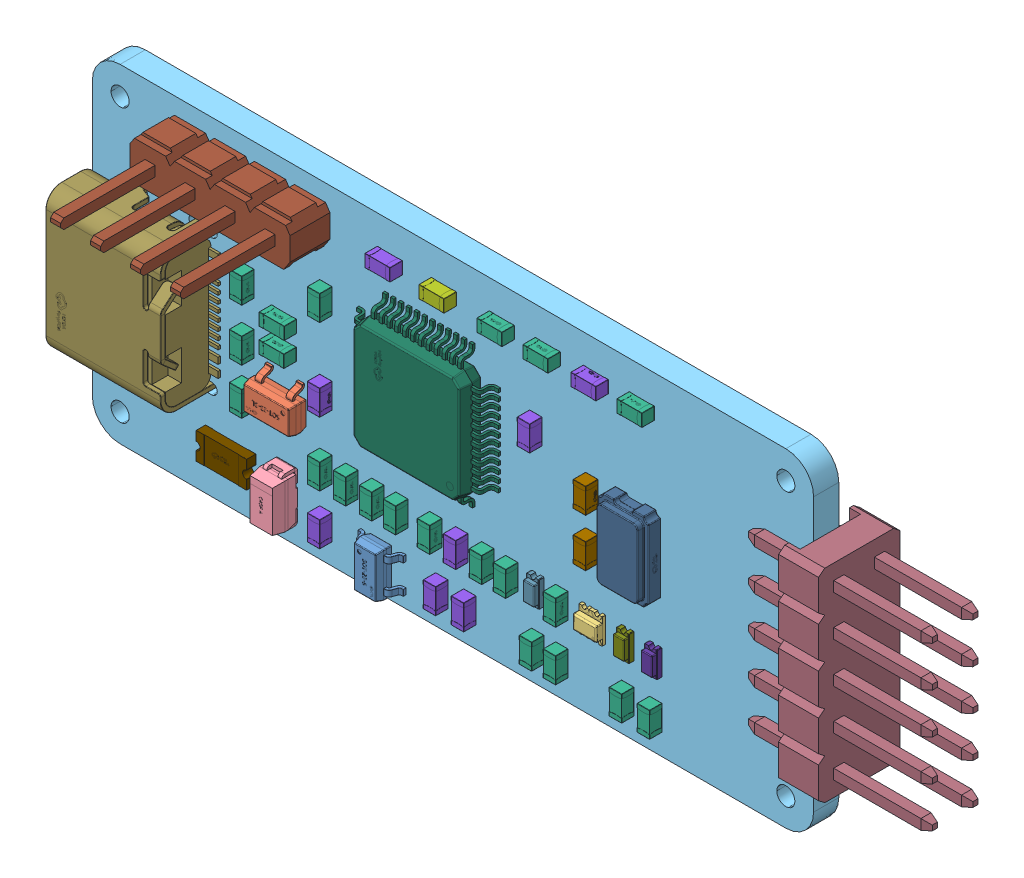
SolidWorks assembly 3D_ST-LINK  V2-1_1_2025-01-13, configuration 默认. Lengths in mm.
Overall size (53.96 20.88 11.97).
51 component instances, 18 part files, 0 mates.
Components (placement in the parent):
- 3D_ST-LINK  V2-1_1_2025-01-13.step-1: 3D_ST-LINK  V2-1_1_2025-01-13.step [默认] at origin size (53.96 20.88 11.97)
  - S64j-U1-SOT-23-5_L3.0-W1.7-P0.95-LS2.8-BR.step-1: S64j-U1-SOT-23-5_L3.0-W1.7-P0.95-LS2.8-BR.step [默认] at (18.5179 2.032 1.6) x (-1 0 0) z (0 0 1) size (2.89 2.78 1.2)
    - COMPOUND.step-1: COMPOUND.step [默认] at origin size (2.89 2.78 1.2)
  - S64j-Q1-SOT-23(SOT-23-3).step-1: S64j-Q1-SOT-23(SOT-23-3).step [默认] at (12.319 6.604 1.6) x (-1 0 0) z (0 0 1) size (3.01 2.92 1.27)
    - COMPOUND-0.step-1: COMPOUND-0.step [默认] at origin size (3.01 2.92 1.27)
  - S64j-LED1-LED-ARRAY-SMD_4P-L1.6-W1.5-TR-RD_TJ-S1615SW6TGLCRB-A5.step-1: S64j-LED1-LED-ARRAY-SMD_4P-L1.6-W1.5-TR-RD_TJ-S1615SW6TGLCRB-A5.step [默认] at (31.8771 5.334 1.6) x (0 -1 0) z (0 0 1) size (1.62 1.51 0.61)
    - COMPOUND-1.step-1: COMPOUND-1.step [默认] at origin size (1.62 1.51 0.61)
  - S64j-C1-CASE-A_3216.step-1: S64j-C1-CASE-A_3216.step [默认] at (12.446 2.921 1.6) x (0 -1 0) z (0 0 1) size (3.2 1.6 1.7)
    - COMPOUND-2.step-1: COMPOUND-2.step [默认] at origin size (3.2 1.6 1.7)
  - S64j-Board.step-1: S64j-Board.step [默认] at origin size (45.82 20.88 1.6)
  - S64j-R12-R0603.step-1: S64j-R12-R0603.step [默认] at (35.8141 2.286 1.6) x (0 1 0) z (0 0 1) size (1.6 0.8 0.8)
  - S64j-R12-R0603.step-2: S64j-R12-R0603.step [默认] at (34.0361 2.286 1.6) x (0 1 0) z (0 0 1) size (1.6 0.8 0.8)
  - S64j-R12-R0603.step-3: S64j-R12-R0603.step [默认] at (29.8451 2.2946 1.6) x (0 1 0) z (0 0 1) size (1.6 0.8 0.8)
  - S64j-R12-R0603.step-4: S64j-R12-R0603.step [默认] at (14.859 14.732 1.6) x (0 1 0) z (0 0 1) size (1.6 0.8 0.8)
  - S64j-R12-R0603.step-5: S64j-R12-R0603.step [默认] at (28.9561 18.796 1.6) size (1.6 0.8 0.8)
  - S64j-R12-R0603.step-6: S64j-R12-R0603.step [默认] at (26.0351 18.796 1.6) size (1.6 0.8 0.8)
  - S64j-R12-R0603.step-7: S64j-R12-R0603.step [默认] at (29.8451 5.461 1.6) x (0 -1 0) z (0 0 1) size (1.6 0.8 0.8)
  - S64j-R12-R0603.step-8: S64j-R12-R0603.step [默认] at (25.1461 5.461 1.6) x (0 1 0) z (0 0 1) size (1.6 0.8 0.8)
  - S64j-R12-R0603.step-9: S64j-R12-R0603.step [默认] at (18.161 5.461 1.6) x (0 -1 0) z (0 0 1) size (1.6 0.8 0.8)
  - S64j-R12-R0603.step-10: S64j-R12-R0603.step [默认] at (14.859 5.461 1.6) x (0 -1 0) z (0 0 1) size (1.6 0.8 0.8)
  - S64j-R12-R0603.step-11: S64j-R12-R0603.step [默认] at (21.844 5.4696 1.6) x (0 -1 0) z (0 0 1) size (1.6 0.8 0.8)
  - S64j-R12-R0603.step-12: S64j-R12-R0603.step [默认] at (16.51 5.461 1.6) x (0 -1 0) z (0 0 1) size (1.6 0.8 0.8)
  - S64j-R12-R0603.step-13: S64j-R12-R0603.step [默认] at (19.685 5.461 1.6) x (0 1 0) z (0 0 1) size (1.6 0.8 0.8)
  - S64j-R12-R0603.step-14: S64j-R12-R0603.step [默认] at (9.906 13.208 1.6) x (0 -1 0) z (0 0 1) size (1.6 0.8 0.8)
  - S64j-R12-R0603.step-15: S64j-R12-R0603.step [默认] at (9.906 6.985 1.6) x (0 1 0) z (0 0 1) size (1.6 0.8 0.8)
  - S64j-R12-R0603.step-16: S64j-R12-R0603.step [默认] at (26.6701 5.461 1.6) x (0 1 0) z (0 0 1) size (1.6 0.8 0.8)
  - S64j-R12-R0603.step-17: S64j-R12-R0603.step [默认] at (9.906 9.906 1.6) x (0 -1 0) z (0 0 1) size (1.6 0.8 0.8)
  - S64j-R12-R0603.step-18: S64j-R12-R0603.step [默认] at (34.9251 18.796 1.6) size (1.6 0.8 0.8)
  - S64j-R12-R0603.step-19: S64j-R12-R0603.step [默认] at (12.2027 12.2134 1.6) size (1.6 0.8 0.8)
  - S64j-R12-R0603.step-20: S64j-R12-R0603.step [默认] at (12.1844 10.668 1.6) size (1.6 0.8 0.8)
  - S64j-R22-R0603.step-1: S64j-R22-R0603.step [默认] at (22.352 18.796 1.6) x (-1 0 0) z (0 0 1) size (1.6 0.8 0.8)
  - S64j-R12-R0603.step-21: S64j-R12-R0603.step [默认] at (28.3211 2.286 1.6) x (0 1 0) z (0 0 1) size (1.6 0.8 0.8)
  - S64j-C2-C0603.step-1: S64j-C2-C0603.step [默认] at (14.859 2.286 1.6) x (0 1 0) z (0 0 1) size (1.6 0.8 0.8)
  - S64j-C2-C0603.step-2: S64j-C2-C0603.step [默认] at (22.225 2.286 1.6) x (0 1 0) z (0 0 1) size (1.6 0.8 0.8)
  - S64j-C5-C0603.step-1: S64j-C5-C0603.step [默认] at (31.7501 12.573 1.6) x (0 -1 0) z (0 0 1) size (1.6 0.8 0.8)
  - S64j-C2-C0603.step-3: S64j-C2-C0603.step [默认] at (32.0041 18.796 1.6) size (1.6 0.8 0.8)
  - S64j-C2-C0603.step-4: S64j-C2-C0603.step [默认] at (18.923 18.796 1.6) x (-1 0 0) z (0 0 1) size (1.6 0.8 0.8)
  - S64j-C2-C0603.step-5: S64j-C2-C0603.step [默认] at (14.859 9.525 1.6) x (0 -1 0) z (0 0 1) size (1.6 0.8 0.8)
  - S64j-C2-C0603.step-6: S64j-C2-C0603.step [默认] at (23.495 5.461 1.6) x (0 1 0) z (0 0 1) size (1.6 0.8 0.8)
  - S64j-C2-C0603.step-7: S64j-C2-C0603.step [默认] at (28.1941 14.224 1.6) x (0 1 0) z (0 0 1) size (1.6 0.8 0.8)
  - S64j-C2-C0603.step-8: S64j-C2-C0603.step [默认] at (24.003 2.286 1.6) x (0 1 0) z (0 0 1) size (1.6 0.8 0.8)
  - S64j-C5-C0603.step-2: S64j-C5-C0603.step [默认] at (31.7501 9.525 1.6) x (0 1 0) z (0 0 1) size (1.6 0.8 0.8)
  - S64j-X1-OSC-SMD_L5.0-W3.2.step-1: S64j-X1-OSC-SMD_L5.0-W3.2.step [默认] at (34.5548 11.0631 1.6) x (0 -1 0) z (0 0 1) size (5 3.2 1.21)
  - S64j-H2-HDR-TH_4P-P2.54-V-M.step-1: S64j-H2-HDR-TH_4P-P2.54-V-M.step [默认] at (10.033 18.796 1.6) x (-1 0 0) z (0 0 1) size (10.17 2.66 11.54)
  - S64j-USB1-USB-3.1-SMD_U262-161N-4BVC11.step-1: S64j-USB1-USB-3.1-SMD_U262-161N-4BVC11.step [默认] at (5.334 10.414 1.6) x (0 -1 0) z (0 0 1) size (8.94 7.9 4.1)
  - S64j-H3-HDR-TH_SMD-10P-P2.54.step-1: S64j-H3-HDR-TH_SMD-10P-P2.54.step [默认] at (42.7991 10.541 1.6) size (11.68 12.9 5.16)
  - S64j-LED2-LED0603.step-1: S64j-LED2-LED0603.step [默认] at (28.3211 5.461 1.6) x (0 -1 0) z (0 0 1) size (1.62 0.8 0.6)
  - S64j-U2-LQFP-48_L7.0-W7.0-P0.50-LS9.0-BL.step-1: S64j-U2-LQFP-48_L7.0-W7.0-P0.50-LS9.0-BL.step [默认] at (21.4566 12.446 1.6) x (0 1 0) z (0 0 1) size (9 9 1.5)
  - S64j-LED3-LED0603.step-1: S64j-LED3-LED0603.step [默认] at (34.0361 5.334 1.6) x (0 -1 0) z (0 0 1) size (1.62 0.8 0.6)
  - S64j-LED4-LED0603.step-1: S64j-LED4-LED0603.step [默认] at (35.8141 5.334 1.6) x (0 -1 0) z (0 0 1) size (1.62 0.8 0.6)
  - S64j-F1-F1206.step-1: S64j-F1-F1206.step [默认] at (8.8113 3.048 1.6) size (3.2 1.7 0.6)
